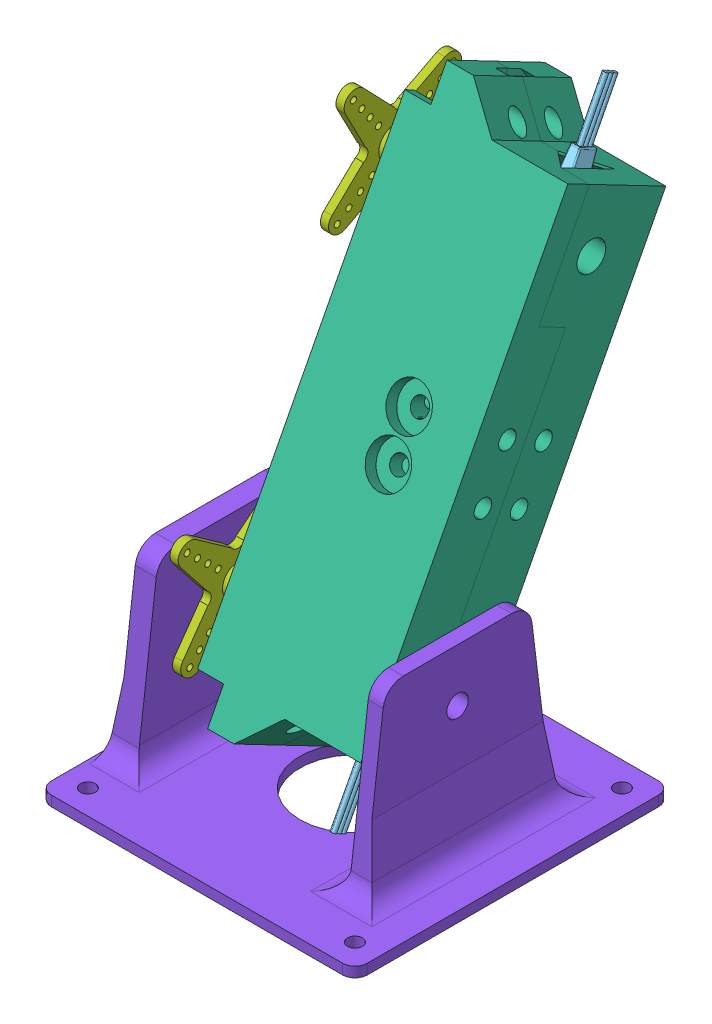
SolidWorks assembly J2, configuration Default. Lengths in mm.
Overall size (77.5 138.06 100.18).
25 component instances, 10 part files, 16 mates.
Components (placement in the parent):
- Servo-1: Servo [Default] at (-12.46 119.8262 -34.3078) x (0 -0.461831 -0.886968) z (-1 0 0) size (20.01 68.31 42.11)
  - Parallax-900-00005-08-25-Servo-CR-HSCR-STD.stp-1: Parallax-900-00005-08-25-Servo-CR-HSCR-STD.stp [Default] at origin size (21 68.31 45.51)
    - SCREW-1.7x24.stp-1: SCREW-1.7x24.stp [Default] at (0 0 -2.6) size (18 38.5 24.9)
      - b4.stp-1: b4.stp [Default] at (12.4 -16.06 -0.6) size (3 3 24.9)
      - b3.stp-1: b3.stp [Default] at (-2.6 -16.06 -0.6) size (3 3 24.9)
      - b2.stp-1: b2.stp [Default] at (-2.6 19.44 -0.6) size (3 3 24.9)
      - b1.stp-1: b1.stp [Default] at (12.4 19.44 -0.6) size (3 3 24.9)
    - HORN-D.stp-1: HORN-D.stp [Default] at (-22.975 33.5463 -1.6) x (1 0 0) z (0 -1 0) size (21 6.2 21) (hidden)
    - Screw_3x8.stp-1: Screw_3x8.stp [Default] at (62.7475 7.2555 -24.6) x (-0.749146 0.662405 0) z (0 0 1) size (5.6 5.6 10.4) (hidden)
    - Case.stp-1: Case.stp [Default] at origin size (20.01 68.31 42.11)
- Joint2Channel-1: Joint2Channel [Default] at (12.65 43.4663 0.4909) x (0 0.886968 -0.461831) z (0 0.461831 0.886968) size (127.08 40 21.04)
- Servo-2: Servo [Default] at (-12.46 18.7921 -4.0241) x (0 0.461831 0.886968) z (-1 0 0) size (20.01 68.31 42.11)
  - Parallax-900-00005-08-25-Servo-CR-HSCR-STD.stp-1: Parallax-900-00005-08-25-Servo-CR-HSCR-STD.stp [Default] at origin size (21 68.31 45.51)
    - SCREW-1.7x24.stp-1: SCREW-1.7x24.stp [Default] at (0 0 -2.6) size (18 38.5 24.9)
      - b4.stp-1: b4.stp [Default] at (12.4 -16.06 -0.6) size (3 3 24.9)
      - b3.stp-1: b3.stp [Default] at (-2.6 -16.06 -0.6) size (3 3 24.9)
      - b2.stp-1: b2.stp [Default] at (-2.6 19.44 -0.6) size (3 3 24.9)
      - b1.stp-1: b1.stp [Default] at (12.4 19.44 -0.6) size (3 3 24.9)
    - HORN-D.stp-1: HORN-D.stp [Default] at (-22.975 33.5463 -1.6) x (1 0 0) z (0 -1 0) size (21 6.2 21) (hidden)
    - Screw_3x8.stp-1: Screw_3x8.stp [Default] at (62.7475 7.2555 -24.6) x (-0.749146 0.662405 0) z (0 0 1) size (5.6 5.6 10.4) (hidden)
    - Case.stp-1: Case.stp [Default] at origin size (20.01 68.31 42.11)
- Joint2Channel-2: Joint2Channel [Default] at (12.65 95.1521 -38.8229) x (0 -0.886968 0.461831) z (0 -0.461831 -0.886968) size (127.08 40 21.04)
- futaba_horn_type_A-1: futaba_horn_type_A [Default] at (-30.5 98.5646 -34.2332) x (0 0.162106 0.986773) z (0 0.986773 -0.162106) size (29.15 5.85 29.15)
- futaba_horn_type_A-2: futaba_horn_type_A [Default] at (-30.5 24.3107 2.6065) x (0 -0.026181 0.999657) z (0 0.999657 0.026181) size (29.15 5.85 29.15)
- Joint2Base-1: Joint2Base [Default] at origin size (77.5 45.5 77.5)
Mates (geometry in assembly coordinates):
- Coincident10: coincident: plane of Joint2Channel-1 through (-13.96 61.3619 -15.028) normal (0 -0.461831 -0.886968); line of Joint2Channel-2 through (-13.96 59.109 -13.8549) axis (0 0.886968 -0.461831)
- Coincident12: coincident aligned: plane of Joint2Channel-1 through (-13.96 43.4663 0.4909) normal (-1 0 0); plane of Joint2Channel-2 through (-13.96 95.1521 -38.8229) normal (-1 0 0)
- Concentric1: concentric aligned: cylinder of Servo-2/Parallax-900-00005-08-25-Servo-CR-HSCR-STD.stp-1/Case.stp-1 through (-26.64 61.2347 -20.5989) axis (1 0 0) radius 2.25; cylinder of Joint2Channel-2 through (-13.96 61.2347 -20.5989) axis (1 0 0) radius 2.16
- Concentric2: concentric aligned: cylinder of Joint2Channel-1 through (-13.96 65.853 -11.7292) axis (1 0 0) radius 2.16; cylinder of Servo-2/Parallax-900-00005-08-25-Servo-CR-HSCR-STD.stp-1/Case.stp-1 through (-26.64 65.853 -11.7292) axis (1 0 0) radius 2.25
- Coincident13: coincident anti-aligned: plane of Joint2Channel-1 through (-13.96 43.4663 0.4909) normal (-1 0 0); plane of Servo-2/Parallax-900-00005-08-25-Servo-CR-HSCR-STD.stp-1/Case.stp-1 through (-13.96 36.8723 -12.9309) normal (1 0 0)
- Concentric4: concentric aligned: cylinder of Servo-1/Parallax-900-00005-08-25-Servo-CR-HSCR-STD.stp-1/Case.stp-1 through (-26.64 77.3836 -17.733) axis (1 0 0) radius 2.25; cylinder of Joint2Channel-1 through (-13.96 77.3836 -17.733) axis (1 0 0) radius 2.16
- Concentric5: concentric anti-aligned: cylinder of Servo-1/Parallax-900-00005-08-25-Servo-CR-HSCR-STD.stp-1/Case.stp-1 through (-26.64 72.7653 -26.6027) axis (1 0 0) radius 2.25; circle of Joint2Channel-2
- Coincident14: coincident anti-aligned: plane of Servo-1/Parallax-900-00005-08-25-Servo-CR-HSCR-STD.stp-1/Case.stp-1 through (-13.96 101.746 -25.4011) normal (1 0 0); plane of Joint2Channel-2 through (-13.96 95.1521 -38.8229) normal (-1 0 0)
- Distance1: distance = 5.24 mm aligned: plane of futaba_horn_type_A-1 through (-30.5 97.6946 -36.9481) normal (-1 0 0); plane of Servo-1/Parallax-900-00005-08-25-Servo-CR-HSCR-STD.stp-1/Case.stp-1 through (-25.26 126.5672 -37.8177) normal (-1 0 0)
- Concentric6: concentric aligned: cylinder of Servo-1/Parallax-900-00005-08-25-Servo-CR-HSCR-STD.stp-1/Case.stp-1 through (-29.46 106.1183 -38.332) axis (-1 0 0) radius 1.1; cylinder of futaba_horn_type_A-1 through (-25.5 106.1183 -38.332) axis (-1 0 0) radius 1.5
- Concentric7: concentric aligned: cylinder of Servo-2/Parallax-900-00005-08-25-Servo-CR-HSCR-STD.stp-1/Case.stp-1 through (-29.46 32.5 0) axis (-1 0 0) radius 1.1; cylinder of futaba_horn_type_A-2 through (-25.5 32.5 0) axis (-1 0 0) radius 1.5
- Distance2: distance = 5.24 mm aligned: plane of futaba_horn_type_A-2 through (-30.5 23.9662 -0.2235) normal (-1 0 0); plane of Servo-2/Parallax-900-00005-08-25-Servo-CR-HSCR-STD.stp-1/Case.stp-1 through (-25.26 12.0511 -0.5142) normal (-1 0 0)
- Coincident15: coordinate: point of Joint2Base-1
- Concentric11: concentric anti-aligned: cylinder of futaba_horn_type_A-2 through (-31.35 32.5 0) axis (1 0 0) radius 3.6; cylinder of Joint2Base-1 through (-25.65 32.5 0) axis (-1 0 0) radius 3.875
- Coincident16: coincident anti-aligned: plane of futaba_horn_type_A-2 through (-30.5 23.9662 -0.2235) normal (-1 0 0); plane of Joint2Base-1 through (-30.5 45.5 -16) normal (1 0 0)
- Angle1: planar angle = 2.52523 rad anti-aligned: plane of futaba_horn_type_A-2 through (-28.5 42.9511 -13.7466) normal (0 -0.578071 -0.815986); plane of Joint2Base-1 through (-38.75 2.5 -38.75) normal (0 0 -1)
